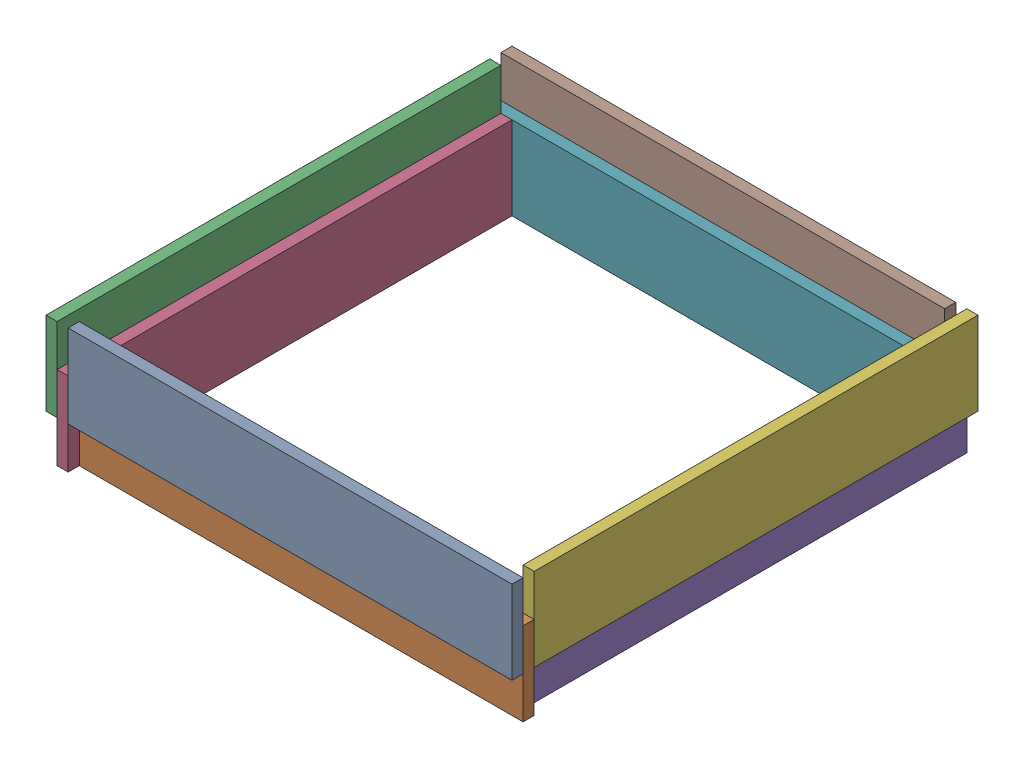
SolidWorks assembly СборкаЯЗ, configuration По умолчанию. Lengths in mm.
Overall size (840 225 840).
12 component instances, 1 part files, 10 mates.
Components (placement in the parent):
- СборкаДЗ-1: СборкаДЗ [По умолчанию] at (400 150 0) x (-1 0 0) z (0 -1 0) size (800 40 225)
  - ДоскаЗ-1: ДоскаЗ [По умолчанию] at origin size (800 20 150)
  - ДоскаЗ-2: ДоскаЗ [По умолчанию] at (0 20 75) size (800 20 150)
- СборкаДЗ-2: СборкаДЗ [По умолчанию] at (-40 150 -400) x (0 0 -1) z (0 -1 0) size (800 40 225)
  - ДоскаЗ-1: ДоскаЗ [По умолчанию] at origin size (800 20 150)
  - ДоскаЗ-2: ДоскаЗ [По умолчанию] at (0 20 75) size (800 20 150)
- СборкаДЗ-3: СборкаДЗ [По умолчанию] at (760 75 -440) x (0 0 1) z (0 1 0) size (800 40 225)
  - ДоскаЗ-1: ДоскаЗ [По умолчанию] at origin size (800 20 150)
  - ДоскаЗ-2: ДоскаЗ [По умолчанию] at (0 20 75) size (800 20 150)
- СборкаДЗ-4: СборкаДЗ [По умолчанию] at (360 75 -800) x (1 0 0) z (0 1 0) size (800 40 225)
  - ДоскаЗ-1: ДоскаЗ [По умолчанию] at origin size (800 20 150)
  - ДоскаЗ-2: ДоскаЗ [По умолчанию] at (0 20 75) size (800 20 150)
Mates (geometry in assembly coordinates):
- Совпадение4: coincident aligned: plane of СборкаДЗ-1/ДоскаЗ-1 through (400 150 0) normal (0 0 1); plane of СборкаДЗ-2/ДоскаЗ-2 through (0 150 0) normal (0 0 1)
- Совпадение5: coincident anti-aligned: plane of СборкаДЗ-1/ДоскаЗ-2 through (0 150 -40) normal (-1 0 0); plane of СборкаДЗ-2/ДоскаЗ-2 through (0 75 -400) normal (1 0 0)
- Совпадение6: coincident aligned: plane of СборкаДЗ-1/ДоскаЗ-1 through (400 150 0) normal (0 0 1); plane of СборкаДЗ-2/ДоскаЗ-1 through (-20 225 0) normal (0 0 1)
- Совпадение7: coincident aligned: plane of СборкаДЗ-1/ДоскаЗ-1 through (800 225 -20) normal (0 1 0); plane of СборкаДЗ-2/ДоскаЗ-1 through (-20 225 0) normal (0 1 0)
- Совпадение8: coincident: plane of СборкаДЗ-1/ДоскаЗ-2 through (400 75 -40) normal (0 0 -1); plane of СборкаДЗ-3/ДоскаЗ-1 through (783.7735 0 -40) normal (0 0 1)
- Совпадение10: coincident: plane of СборкаДЗ-1/ДоскаЗ-1 through (800 225 -20) normal (0 1 0); plane of СборкаДЗ-3/ДоскаЗ-2 through (800 225 -840) normal (0 1 0)
- Совпадение11: coincident aligned: plane of СборкаДЗ-1/ДоскаЗ-2 through (800 150 -40) normal (1 0 0); plane of СборкаДЗ-3/ДоскаЗ-2 through (800 150 -440) normal (1 0 0)
- Совпадение12: coincident: plane of СборкаДЗ-3/ДоскаЗ-2 through (800 225 -840) normal (0 1 0); plane of СборкаДЗ-4/ДоскаЗ-2 through (-40 225 -840) normal (0 1 0)
- Совпадение13: coincident: plane of СборкаДЗ-2/ДоскаЗ-2 through (0 150 -800) normal (0 0 -1); plane of СборкаДЗ-4/ДоскаЗ-1 through (360 75 -800) normal (0 0 1)
- Совпадение14: coincident aligned: plane of СборкаДЗ-2/ДоскаЗ-1 through (-40 150 -400) normal (-1 0 0); plane of СборкаДЗ-4/ДоскаЗ-2 through (-40 75 -840) normal (-1 0 0)
